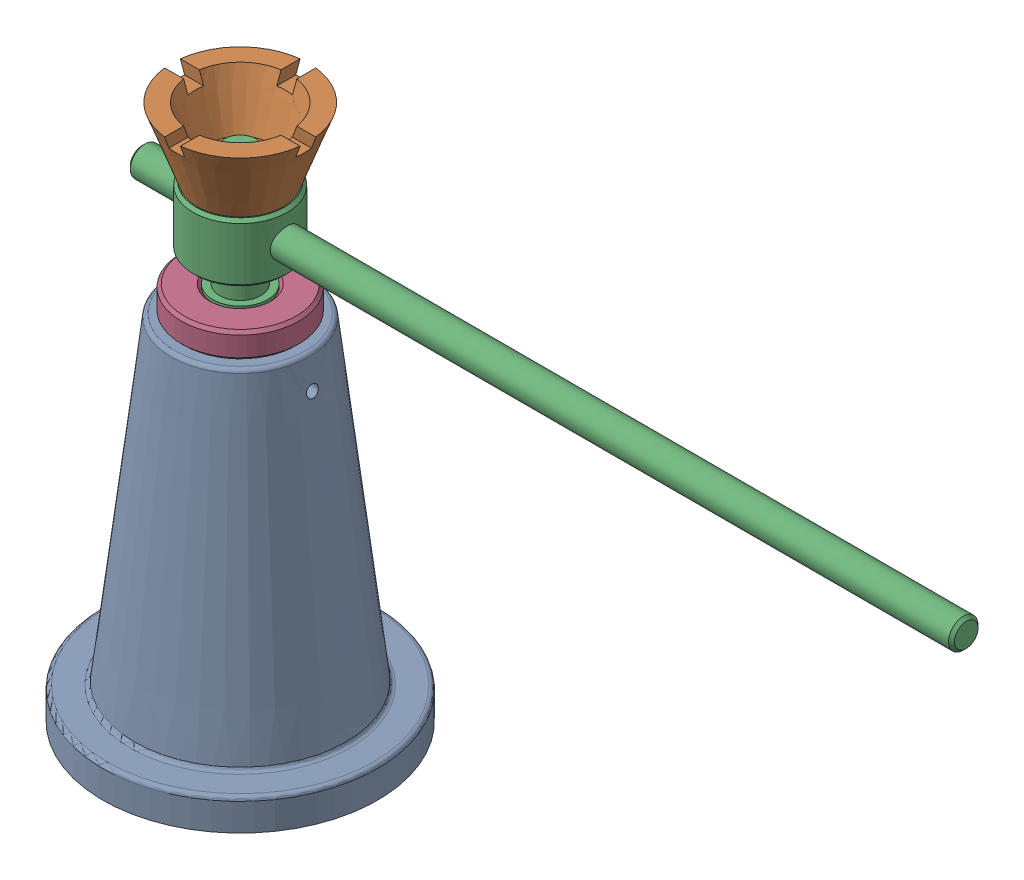
SolidWorks assembly 螺旋式起重器, configuration 默认. Lengths in mm.
Overall size (440 273 140).
4 component instances, 4 part files, 7 mates.
Components (placement in the parent):
- 底座-2: 底座 [默认] at origin size (140 180 140)
- 杯托-1: 杯托 [默认] at (0 238 0) x (1 0 0) z (0 -1 0) size (69.02 69.02 35)
- 螺杆-1: 螺杆 [默认] at (0 28 0) x (0 0 -1) z (1 0 0) size (48 225 420)
- 螺母-2: 螺母 [默认] at (0 148 0) size (60 45 60)
Mates (geometry in assembly coordinates):
- 同心2: concentric anti-aligned: cylinder of 底座-2 through (0 -0.001 0) axis (0 1 0) radius 21; cylinder of 螺母-2 through (0 180 0) axis (0 -1 0) radius 21
- 重合2: coincident anti-aligned: plane of 底座-2 through (-35 180 0) normal (0 1 0); plane of 螺母-2 through (0 180 0) normal (0 -1 0)
- 同心3: concentric anti-aligned: cylinder of 螺杆-1 through (0 193 0) axis (0 -1 0) radius 14; cylinder of 螺母-2 through (0 148 0) axis (0 1 0) radius 14
- 重合4: coincident anti-aligned: plane of 杯托-1 through (0 238 0) normal (0 -1 0); plane of 螺杆-1 through (0 238 0) normal (0 1 0)
- 同心4: concentric aligned: circle of 杯托-1; cylinder of 螺杆-1 through (0 253 0) axis (0 -1 0) radius 8
- 平行1: parallel aligned: cylinder of 螺杆-1 through (-50 223 0) axis (1 0 0) radius 7.5
- 重合5: coincident aligned: plane of 螺杆-1 through (0 193 0) normal (0 1 0); plane of 螺母-2 through (0 193 0) normal (0 1 0)
